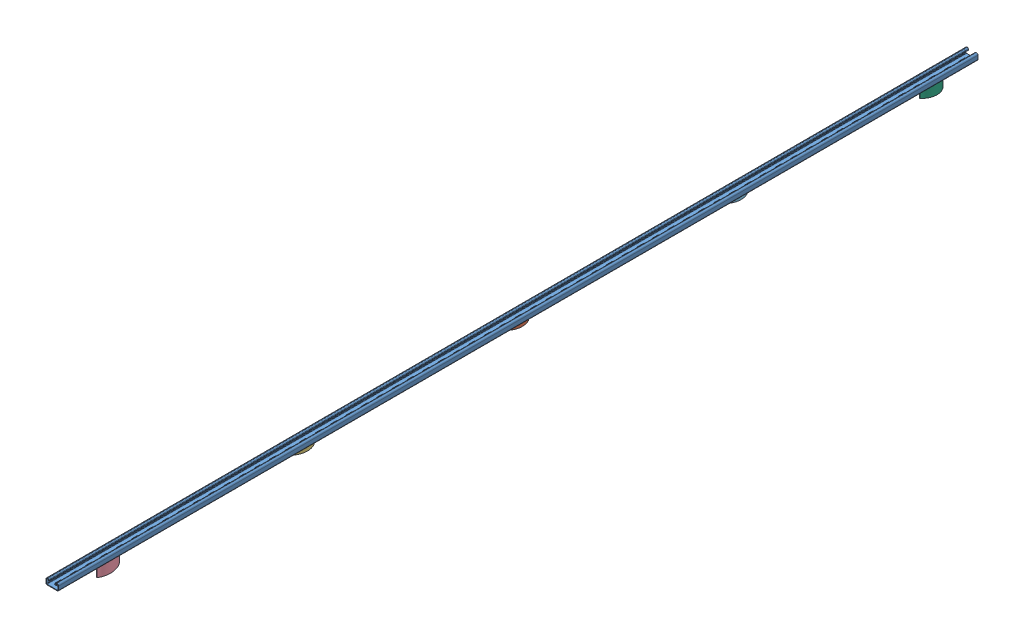
SolidWorks assembly Roof Rack Stut, configuration Default. Lengths in mm.
Overall size (41.28 67.43 3048).
6 component instances, 6 part files, 10 mates.
Components (placement in the parent):
- 3310T8_Strut Channel-1: 3310T8_Strut Channel [3310T8] at (-622.3 1893.0006 957.7806) x (0 -1 0) z (0 0 1) size (20.64 41.27 3048)
- Center Spacer V1-1: Center Spacer V1 [Default] at (-622.3 1880.3006 -584.4756) size (31.75 16.33 76.2)
- Front Center Spacer V1-1: Front Center Spacer V1 [Default] at (-622.3 1878.7131 126.7244) size (31.75 18.31 76.2)
- Front Spacer V1-1: Front Spacer V1 [Default] at (-622.3 1854.9006 772.8369) size (31.75 46.79 76.2)
- Rear Center Spacer V1-1: Rear Center Spacer V1 [Default] at (-622.3 1881.8881 -1309.9631) size (31.75 14.47 76.2)
- Rear Spacer V1-1: Rear Spacer V1 [Default] at (-622.3 1858.0756 -1956.0756) size (31.75 40.44 76.2)
Mates (geometry in assembly coordinates):
- Coincident2: coincident anti-aligned: plane of 3310T8_Strut Channel-1 through (-605.1232 1893.0006 -2090.2194) normal (0 -1 0); plane of Front Spacer V1-1 through (-638.175 1893.0006 810.9369) normal (0 1 0)
- Coincident3: coincident anti-aligned: plane of 3310T8_Strut Channel-1 through (-605.1232 1893.0006 -2090.2194) normal (0 -1 0); plane of Center Spacer V1-1 through (-638.175 1893.0006 -546.3756) normal (0 1 0)
- Coincident5: coincident anti-aligned: plane of 3310T8_Strut Channel-1 through (-605.1232 1893.0006 -2090.2194) normal (0 -1 0); plane of Front Center Spacer V1-1 through (-638.175 1893.0006 164.8244) normal (0 1 0)
- Coincident6: coincident anti-aligned: plane of 3310T8_Strut Channel-1 through (-605.1232 1893.0006 -2090.2194) normal (0 -1 0); plane of Rear Center Spacer V1-1 through (-638.175 1893.0006 -1271.8631) normal (0 1 0)
- Coincident7: coincident anti-aligned: plane of 3310T8_Strut Channel-1 through (-605.1232 1893.0006 -2090.2194) normal (0 -1 0); plane of Rear Spacer V1-1 through (-638.175 1893.0006 -1917.9756) normal (0 1 0)
- Concentric1: concentric anti-aligned: cylinder of 3310T8_Strut Channel-1 through (-622.3 1895.0326 772.8369) axis (0 -1 0) radius 7.1437; cylinder of Front Spacer V1-1 through (-622.3 1849.2995 772.8369) axis (0 1 0) radius 6.5
- Concentric2: concentric anti-aligned: cylinder of 3310T8_Strut Channel-1 through (-622.3 1895.0326 126.7244) axis (0 -1 0) radius 7.1437; cylinder of Front Center Spacer V1-1 through (-622.3 1877.7861 126.7244) axis (0 1 0) radius 6.5
- Concentric3: concentric anti-aligned: cylinder of 3310T8_Strut Channel-1 through (-622.3 1895.0326 -584.4756) axis (0 -1 0) radius 7.1437; cylinder of Center Spacer V1-1 through (-622.3 1879.7641 -584.4756) axis (0 1 0) radius 6.5
- Concentric4: concentric anti-aligned: cylinder of 3310T8_Strut Channel-1 through (-622.3 1895.0326 -1309.9631) axis (0 -1 0) radius 7.1437; cylinder of Rear Center Spacer V1-1 through (-622.3 1881.6284 -1309.9631) axis (0 1 0) radius 6.5
- Concentric5: concentric anti-aligned: cylinder of 3310T8_Strut Channel-1 through (-622.3 1895.0326 -1956.0756) axis (0 -1 0) radius 7.1437; cylinder of Rear Spacer V1-1 through (-622.3 1855.6512 -1956.0756) axis (0 1 0) radius 6.5
